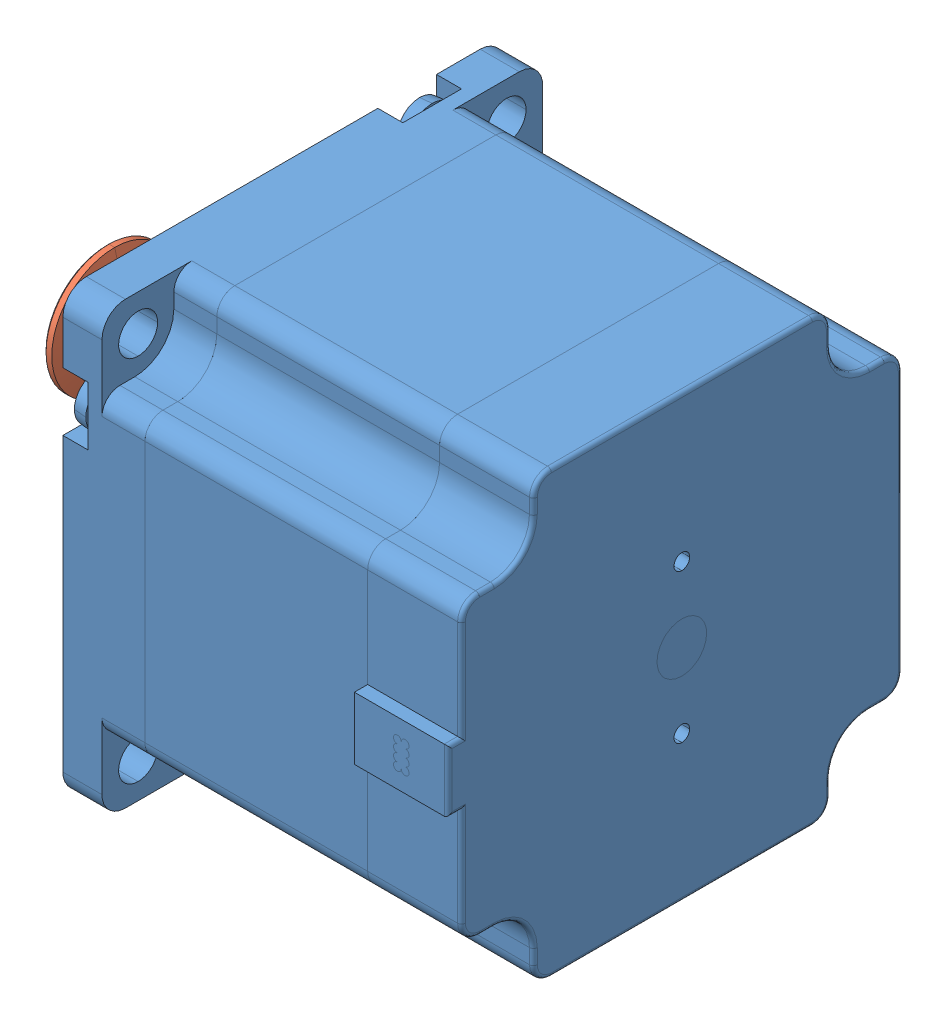
SolidWorks assembly NEMA23_ASSY, configuration Default. Lengths in mm.
Overall size (73.61 56.94 58.38).
5 component instances, 4 part files, 0 mates.
Components (placement in the parent):
- NEMA23_ASSY.stp-1: NEMA23_ASSY.stp [Default] at origin size (73.61 117.68 64.11)
  - Copy (1) of Nema23_Step_Motor.stp-1: Copy (1) of Nema23_Step_Motor.stp [Default] at (412.5997 120.0995 -299.8998) x (0.000001 1 0) z (-1 0.000001 -0.000002) size (56.94 58.38 71.61)
  - GT2_Timing_Pulley_20T_10mm_Hole_5mm.stp-1: GT2_Timing_Pulley_20T_10mm_Hole_5mm.stp [Default] at (371.7997 120.0996 -299.8998) x (0.000001 0.999977 -0.006776) z (-1 0.000001 -0.000002) size (16.01 16.05 20.01)
  - GT2_Timing_Pulley_40T_10mm_Bore_10mm.stp-1: GT2_Timing_Pulley_40T_10mm_Bore_10mm.stp [Default] at (377.3996 44.888 -320.1) x (0.000001 0 -1) z (-1 0 -0.000001) size (28 28 21) (hidden)
  - Y_Kayis1.stp-1: Y_Kayis1.stp [Default] at origin size (10 97.21 42.2) (hidden)
